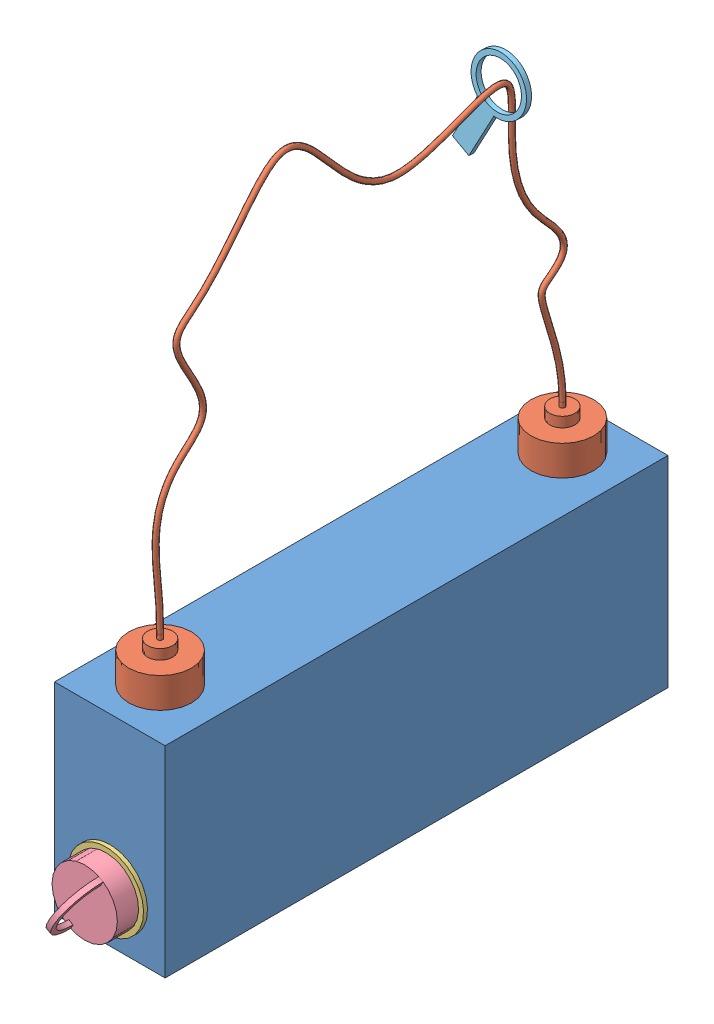
SolidWorks assembly lec36-path-mate-linear-coupler, configuration Default. Lengths in mm.
Overall size (57.4 307.6 283.21).
5 component instances, 5 part files, 22 mates.
Components (placement in the parent):
- Main Part_Path Mate-1: Main Part_Path Mate [Default] at (91.5285 149.8343 184.9571) size (55.88 101.6 254)
- Copy of Copy of Copy of Part3^lec36-path-mate-linear-coupler-1: Copy of Copy of Copy of Part3^lec36-path-mate-linear-coupler [Default] at (91.5285 200.6343 184.9571) x (1 0 0) z (0 1 0) size (31.75 234.95 254.26) (virtual)
- Part4^lec36-path-mate-linear-coupler-1: Part4^lec36-path-mate-linear-coupler [Default] at (67.487 132.6298 313.9605) x (0.322658 0.946515 0) z (0 0 1) size (38.1 38.1 228.6) (virtual)
- Part5^lec36-path-mate-linear-coupler-1: Part5^lec36-path-mate-linear-coupler [Default] at (78.8607 102.4187 311.9571) x (-0.866755 0.498734 0) z (0 0 1) size (33.02 33.02 245.11) (virtual)
- Part6^lec36-path-mate-linear-coupler-1: Part6^lec36-path-mate-linear-coupler [Default] at (91.5285 377.435 115.4634) x (-0.894161 0.446704 -0.03052) z (0 -0.068164 -0.997674) size (27.94 51.88 2.54) (virtual)
Mates (geometry in assembly coordinates):
- InPlace1: in place: plane of Main Part_Path Mate-1 through (123.2785 200.6343 57.9571) normal (0 1 0); plane of ? through (0 200.6343 0) normal (0 1 0); moOrthogonalPlaneRef_w of Main Part_Path Mate-1 through (123.2785 200.6343 57.9571) normal (0 1 0); plane of ? through (0 200.6343 0) normal (0 0 -1); plane of Main Part_Path Mate-1 through (123.2785 200.6343 57.9571) normal (0 1 0); line of ? through (-55 0 200.6343) axis (0 1 0); plane of Main Part_Path Mate-1 through (119.4685 200.6343 57.9571) normal (0 1 0); unknown of Copy of Copy of Copy of Part3^lec36-path-mate-linear-coupler-1
- Coincident1: coincident aligned: plane of Main Part_Path Mate-1; plane of Copy of Copy of Copy of Part3^lec36-path-mate-linear-coupler-1
- Coincident2: coincident aligned: moOrthogonalPlaneRef_w of Main Part_Path Mate-1 through (91.5285 200.6343 184.9571) normal (0 0 -1); plane of Copy of Copy of Copy of Part3^lec36-path-mate-linear-coupler-1 through (91.5285 200.6343 184.9571) normal (0 0 -1)
- Coincident3: coincident anti-aligned: moOrthogonalPlaneRef_w of Main Part_Path Mate-1 through (91.5285 200.6343 184.9571) normal (-1 0 0); plane of Copy of Copy of Copy of Part3^lec36-path-mate-linear-coupler-1 through (91.5285 200.6343 184.9571) normal (1 0 0)
- InPlace2: in place: plane of Main Part_Path Mate-1 through (123.2785 200.6343 311.9571) normal (0 0 1); plane of ? through (0 0 311.9571) normal (0 0 1); plane of Main Part_Path Mate-1 through (123.2785 200.6343 311.9571) normal (0 0 1); plane of ? through (0 0 311.9571) normal (0 1 0); plane of Main Part_Path Mate-1 through (123.2785 200.6343 311.9571) normal (0 0 1); plane of ? through (0 0 311.9571) normal (1 0 0); plane of Main Part_Path Mate-1 through (119.4685 200.6343 311.9571) normal (0 0 1); unknown of ?
- Coincident1: coincident: plane of Main Part_Path Mate-1; plane of Part4^lec36-path-mate-linear-coupler-1
- Coincident2: coincident aligned: moOrthogonalPlaneRef_w of Main Part_Path Mate-1 through (91.5285 149.8343 311.9571) normal (0 1 0); plane of Part4^lec36-path-mate-linear-coupler-1
- Coincident3: coincident anti-aligned: moOrthogonalPlaneRef_w of Main Part_Path Mate-1 through (91.5285 149.8343 311.9571) normal (-1 0 0); plane of Part4^lec36-path-mate-linear-coupler-1
- InPlace3: in place: plane of Main Part_Path Mate-1 through (123.2785 200.6343 311.9571) normal (0 0 1); plane of ? through (0 0 311.9571) normal (0 0 1); plane of Main Part_Path Mate-1 through (123.2785 200.6343 311.9571) normal (0 0 1); plane of ? through (0 0 311.9571) normal (0 1 0); plane of Main Part_Path Mate-1 through (123.2785 200.6343 311.9571) normal (0 0 1); plane of ? through (0 0 311.9571) normal (1 0 0); plane of Main Part_Path Mate-1 through (119.4685 200.6343 311.9571) normal (0 0 1); unknown of ?
- Coincident4: coincident: plane of Main Part_Path Mate-1; plane of Part5^lec36-path-mate-linear-coupler-1
- Coincident5: coincident aligned: moOrthogonalPlaneRef_w of Main Part_Path Mate-1 through (91.5285 149.8343 311.9571) normal (0 1 0); plane of Part5^lec36-path-mate-linear-coupler-1
- Coincident6: coincident anti-aligned: moOrthogonalPlaneRef_w of Main Part_Path Mate-1 through (91.5285 149.8343 311.9571) normal (-1 0 0); plane of Part5^lec36-path-mate-linear-coupler-1
- InPlace4: in place: plane of Main Part_Path Mate-1 through (63.5885 149.8343 184.9571) normal (-1 0 0); plane of ? through (63.5885 0 0) normal (-1 0 0); plane of Main Part_Path Mate-1 through (63.5885 149.8343 184.9571) normal (-1 0 0); line of ? through (-55 63.5885 0) axis (0 0 1); plane of Main Part_Path Mate-1 through (63.5885 149.8343 184.9571) normal (-1 0 0); plane of ? through (63.5885 0 0) normal (0 0 1); plane of Main Part_Path Mate-1 through (63.5885 149.8343 184.9571) normal (-1 0 0); unknown of ?
- Coincident7: coincident aligned: plane of Main Part_Path Mate-1; plane of Part6^lec36-path-mate-linear-coupler-1
- Coincident8: coincident aligned: moOrthogonalPlaneRef_w of Main Part_Path Mate-1 through (63.5885 149.8343 184.9571) normal (0 1 0); plane of Part6^lec36-path-mate-linear-coupler-1
- Coincident9: coincident anti-aligned: moOrthogonalPlaneRef_w of Main Part_Path Mate-1 through (63.5885 149.8343 184.9571) normal (0 0 -1); plane of Part6^lec36-path-mate-linear-coupler-1
- Concentric1: concentric aligned: cylinder of Main Part_Path Mate-1 through (91.5285 124.4343 4.0756) axis (0 0 1) radius 19.05; cylinder of Part4^lec36-path-mate-linear-coupler-1 through (91.5285 124.4343 85.3605) axis (0 0 1) radius 19.05
- Concentric2: concentric aligned: cylinder of Main Part_Path Mate-1 through (91.5285 124.4343 4.0756) axis (0 0 1) radius 19.05; cylinder of Part5^lec36-path-mate-linear-coupler-1 through (91.5285 124.4343 96.0571) axis (0 0 1) radius 16.51
- LimitDistance1: limit distance = 12.7 mm aligned: plane of Part5^lec36-path-mate-linear-coupler-1 through (91.5285 124.4343 324.6571) normal (0 0 1); plane of Main Part_Path Mate-1 through (119.4685 200.6343 311.9571) normal (0 0 1)
- LimitDistance2: limit distance = 2.0034 mm aligned: plane of Part4^lec36-path-mate-linear-coupler-1 through (91.5285 124.4343 313.9605) normal (0 0 1); plane of Main Part_Path Mate-1 through (119.4685 200.6343 311.9571) normal (0 0 1)
- PathMate1: path: point of Part6^lec36-path-mate-linear-coupler-1; curve of Copy of Copy of Copy of Part3^lec36-path-mate-linear-coupler-1
- Linear/Linear Coupler2: linear coupler = 76.2 : 25.4 mm: plane of Part5^lec36-path-mate-linear-coupler-1 through (91.5285 124.4343 324.6571) normal (0 0 1); cylinder of Part4^lec36-path-mate-linear-coupler-1 through (91.5285 124.4343 85.3605) axis (0 0 1) radius 19.05
